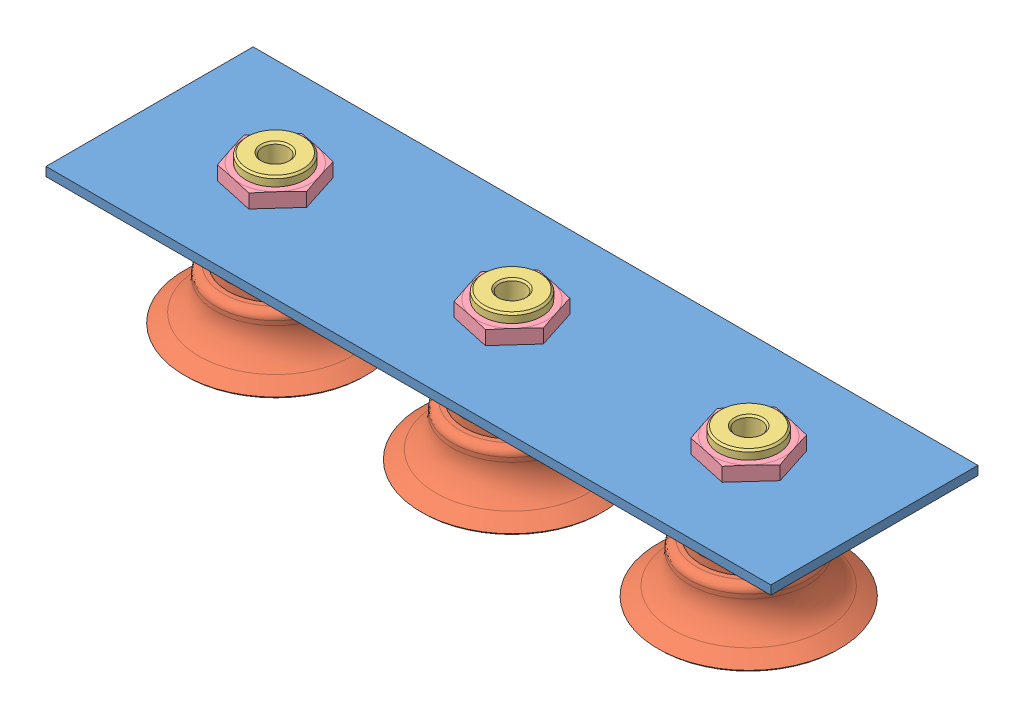
SolidWorks assembly VACCUM_ASSY, configuration Default. Lengths in mm.
Overall size (245 50.6 77.33).
16 component instances, 4 part files, 1 mates.
Components (placement in the parent):
- vaccum support plate-1: vaccum support plate [Default] at (69.0576 105.1376 156.4307) x (-1 0 0) z (0 1 0) size (245 70 3)
- 189177 ESG-60-SN-HA-G---(0_0).stp-1: 189177 ESG-60-SN-HA-G---(0_0).stp [Default] at (-10.9424 85.9533 156.4307) x (0.952335 0 -0.305053) z (0.305053 0 0.952335) size (61.5 50.6 61.5)
  - _189314 ESS-60-SN.stp-1: _189314 ESS-60-SN.stp [Default] at (0 -20.6 0) size (61.5 25.1 61.5)
  - _189201 ESH-HA-5-G.stp-1: _189201 ESH-HA-5-G.stp [Default] at origin size (25.41 30 25.41)
  - _130520 ESHM-M20x1.stp-1: _130520 ESHM-M20x1.stp [Default] at (0 12 0) size (27.73 5.01 27.73)
  - _130520 ESHM-M20x1.stp-2: _130520 ESHM-M20x1.stp [Default] at (0 22 0) size (27.73 5.01 27.73)
- 189177 ESG-60-SN-HA-G---(0_0).stp-2: 189177 ESG-60-SN-HA-G---(0_0).stp [Default] at (69.0576 85.9533 156.4307) x (0.952335 0 -0.305053) z (0.305053 0 0.952335) size (61.5 50.6 61.5)
  - _189314 ESS-60-SN.stp-1: _189314 ESS-60-SN.stp [Default] at (0 -20.6 0) size (61.5 25.1 61.5)
  - _189201 ESH-HA-5-G.stp-1: _189201 ESH-HA-5-G.stp [Default] at origin size (25.41 30 25.41)
  - _130520 ESHM-M20x1.stp-1: _130520 ESHM-M20x1.stp [Default] at (0 12 0) size (27.73 5.01 27.73)
  - _130520 ESHM-M20x1.stp-2: _130520 ESHM-M20x1.stp [Default] at (0 22 0) size (27.73 5.01 27.73)
- 189177 ESG-60-SN-HA-G---(0_0).stp-3: 189177 ESG-60-SN-HA-G---(0_0).stp [Default] at (149.0576 85.9533 156.4307) x (0.952335 0 -0.305053) z (0.305053 0 0.952335) size (61.5 50.6 61.5)
  - _189314 ESS-60-SN.stp-1: _189314 ESS-60-SN.stp [Default] at (0 -20.6 0) size (61.5 25.1 61.5)
  - _189201 ESH-HA-5-G.stp-1: _189201 ESH-HA-5-G.stp [Default] at origin size (25.41 30 25.41)
  - _130520 ESHM-M20x1.stp-1: _130520 ESHM-M20x1.stp [Default] at (0 12 0) size (27.73 5.01 27.73)
  - _130520 ESHM-M20x1.stp-2: _130520 ESHM-M20x1.stp [Default] at (0 22 0) size (27.73 5.01 27.73)
Mates (geometry in assembly coordinates):
- Concentric1: concentric: cylinder of vaccum support plate-1 through (-10.9424 105.1376 156.4307) axis (0 1 0) radius 10; cylinder of 189177 ESG-60-SN-HA-G---(0_0).stp-1/_189201 ESH-HA-5-G.stp-1 through (-10.9424 85.9533 156.4307) axis (0 1 0) radius 9.3865
